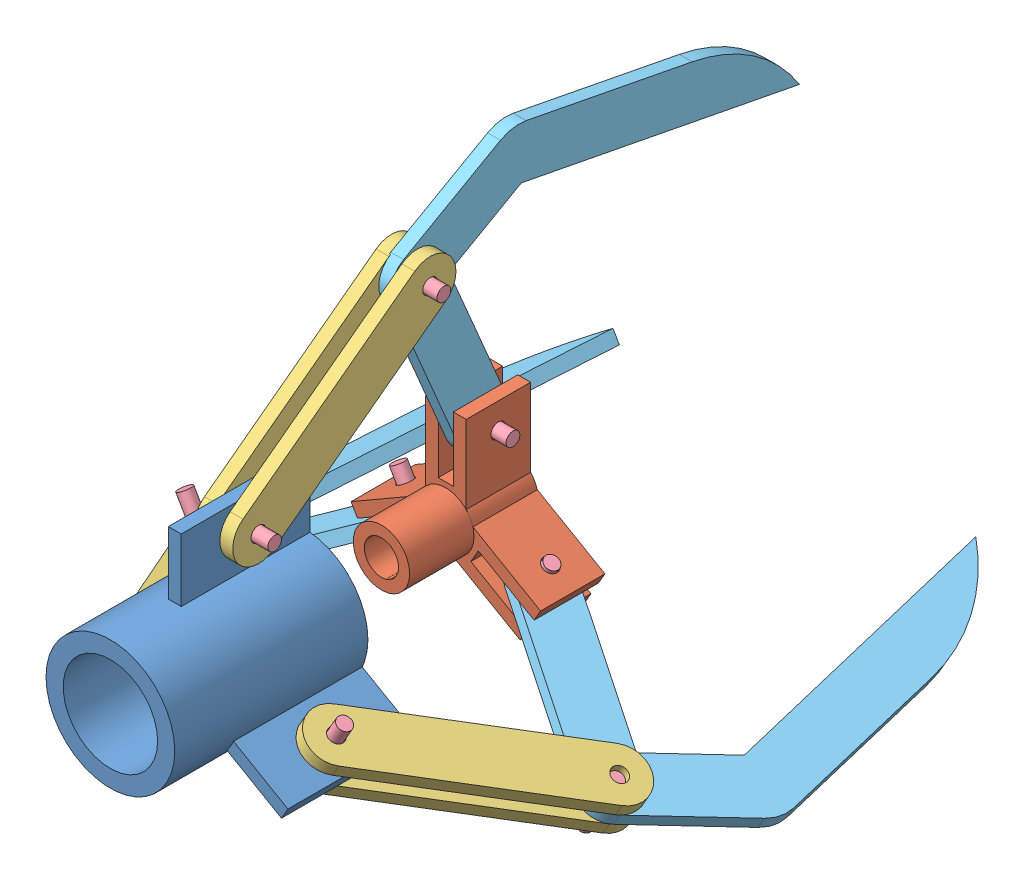
SolidWorks assembly 夾爪成品, configuration 預設. Lengths in mm.
Overall size (162.59 141.13 161.62).
20 component instances, 5 part files, 38 mates.
Components (placement in the parent):
- 電磁鐵放置區-1: 電磁鐵放置區 [預設] at (-9.8898 1.8598 -8.132) size (52.72 45.66 45)
- 三向夾物臂連接器-1: 三向夾物臂連接器 [預設] at (-9.8898 1.8598 -56.2732) x (-0.5 0.866025 0) z (0.866025 0.5 0) size (44.14 30 38.23)
- 夾物臂連接圓軸-1: 夾物臂連接圓軸 [預設] at (11.2751 -8.6277 6.868) x (0.519411 -0.299882 -0.800177) z (0.692973 -0.400088 0.599765) size (62 3 12)
- M3螺絲模擬-2: M3螺絲模擬 [預設] at (7.158 -15.7587 6.868) x (0.823092 -0.475212 0.310955) z (-0.269295 0.155477 0.950425) size (3.2 15 3.2)
- 夾物臂連接圓軸-2: 夾物臂連接圓軸 [預設] at (8.2751 -13.8239 6.868) x (0.519411 -0.299882 -0.800177) z (0.692973 -0.400088 0.599765) size (62 3 12)
- 夾物臂-1: 夾物臂 [預設] at (5.3596 -5.2124 -48.7732) x (0.797152 -0.460236 0.390809) z (0.338451 -0.195405 -0.920472) size (54.96 3 86)
- M3螺絲模擬-3: M3螺絲模擬 [預設] at (30.5045 -35.2978 -33.1408) x (0.866025 -0.5 0) z (0 0 1) size (3.2 15 3.2)
- M3螺絲模擬-4: M3螺絲模擬 [預設] at (-0.1826 -14.8118 -48.7732) x (-0.023911 0.013805 -0.999619) z (0.865695 -0.499809 -0.027609) size (3.2 15 3.2)
- 夾物臂-2: 夾物臂 [預設] at (-23.5141 -8.027 -48.7732) x (-0.797152 -0.460236 0.390809) z (-0.338451 -0.195405 -0.920472) size (54.96 3 86)
- M3螺絲模擬-5: M3螺絲模擬 [預設] at (-55.0827 -26.9864 -33.1408) x (0.866025 0.5 0) z (0 0 1) size (3.2 15 3.2)
- M3螺絲模擬-6: M3螺絲模擬 [預設] at (-20.9793 -12.4174 -48.7732) x (0.832749 0.480788 -0.274541) z (0.237759 0.13727 0.961576) size (3.2 15 3.2)
- 夾物臂連接圓軸-3: 夾物臂連接圓軸 [預設] at (-53.9002 -29.0345 -33.1408) x (0.519411 0.299882 0.800177) z (-0.692973 -0.400088 0.599765) size (62 3 12)
- 夾物臂連接圓軸-4: 夾物臂連接圓軸 [預設] at (-56.9002 -23.8383 -33.1408) x (0.519411 0.299882 0.800177) z (-0.692973 -0.400088 0.599765) size (62 3 12)
- M3螺絲模擬-7: M3螺絲模擬 [預設] at (-26.9948 -15.6596 6.868) x (0.855858 0.49413 0.152782) z (-0.132313 -0.076391 0.98826) size (3.2 15 3.2)
- M3螺絲模擬-8: M3螺絲模擬 [預設] at (-1.7523 18.6022 -48.7732) x (0 0.714644 0.699488) z (0 -0.699488 0.714644) size (3.2 15 3.2)
- M3螺絲模擬-9: M3螺絲模擬 [預設] at (-16.6217 25.4328 6.868) x (0 -0.623006 0.782217) z (0 0.782217 0.623006) size (3.2 15 3.2)
- M3螺絲模擬-10: M3螺絲模擬 [預設] at (-2.2035 55.421 -33.1408) x (0 0.967344 0.253466) z (0 -0.253466 0.967344) size (3.2 15 3.2)
- 夾物臂-3: 夾物臂 [預設] at (-11.6398 18.6022 -48.7732) x (0 0.920472 0.390809) z (0 0.390809 -0.920472) size (54.96 3 86)
- 夾物臂連接圓軸-5: 夾物臂連接圓軸 [預設] at (-11.3898 25.4328 6.868) x (0 0.599765 -0.800177) z (0 0.800177 0.599765) size (62 3 12)
- 夾物臂連接圓軸-6: 夾物臂連接圓軸 [預設] at (-5.3898 25.4328 6.868) x (0 0.599765 -0.800177) z (0 0.800177 0.599765) size (62 3 12)
Mates (geometry in assembly coordinates):
- 同軸心1: concentric anti-aligned: cylinder of 電磁鐵放置區-1 through (-9.8898 1.8598 -8.132) axis (0 0 1) radius 7.5; cylinder of 三向夾物臂連接器-1 through (-9.8898 1.8598 -26.2732) axis (0 0 -1) radius 6.575
- 平行(R)1: parallel aligned: plane of 電磁鐵放置區-1 through (14.9712 -14.2258 21.868) normal (-0.5 -0.866025 0); plane of 三向夾物臂連接器-1 through (-8.3248 -4.5286 -41.2732) normal (-0.5 -0.866025 0)
- 同軸心2: concentric aligned: cylinder of 電磁鐵放置區-1 through (24.7751 14.755 6.868) axis (-0.5 -0.866025 0) radius 1.75; cylinder of M3螺絲模擬-2 through (14.658 -2.7683 6.868) axis (-0.5 -0.866025 0) radius 1.6
- 同軸心3: concentric aligned: cylinder of 夾物臂連接圓軸-1 through (12.7751 -6.0296 6.868) axis (-0.5 -0.866025 0) radius 1.75; cylinder of M3螺絲模擬-2 through (14.658 -2.7683 6.868) axis (-0.5 -0.866025 0) radius 1.6
- 重合/共線/共點4: coincident anti-aligned: plane of 電磁鐵放置區-1 through (16.4712 -11.6277 21.868) normal (0.5 0.866025 0); plane of 夾物臂連接圓軸-1 through (11.2751 -8.6277 6.868) normal (-0.5 -0.866025 0)
- 重合/共線/共點5: coincident anti-aligned: plane of 電磁鐵放置區-1 through (14.9712 -14.2258 21.868) normal (-0.5 -0.866025 0); plane of 夾物臂連接圓軸-2 through (9.7751 -11.2258 6.868) normal (0.5 0.866025 0)
- 同軸心20: concentric aligned: cylinder of M3螺絲模擬-2 through (14.658 -2.7683 6.868) axis (-0.5 -0.866025 0) radius 1.6; cylinder of 夾物臂連接圓軸-2 through (9.7751 -11.2258 6.868) axis (-0.5 -0.866025 0) radius 1.75
- 同軸心21: concentric aligned: cylinder of 夾物臂連接圓軸-1 through (38.7456 -21.0238 -33.1408) axis (-0.5 -0.866025 0) radius 1.75; cylinder of 夾物臂連接圓軸-2 through (35.7456 -26.2199 -33.1408) axis (-0.5 -0.866025 0) radius 1.75
- 同軸心22: concentric aligned: cylinder of 夾物臂連接圓軸-2 through (35.7456 -26.2199 -33.1408) axis (-0.5 -0.866025 0) radius 1.75; cylinder of M3螺絲模擬-3 through (38.0045 -22.3074 -33.1408) axis (-0.5 -0.866025 0) radius 1.6
- 同軸心23: concentric anti-aligned: cylinder of 夾物臂-1 through (35.7456 -26.2199 -33.1408) axis (0.5 0.866025 0) radius 1.75; cylinder of M3螺絲模擬-3 through (38.0045 -22.3074 -33.1408) axis (-0.5 -0.866025 0) radius 1.6
- 重合/共線/共點6: coincident anti-aligned: plane of 夾物臂連接圓軸-2 through (9.7751 -11.2258 6.868) normal (0.5 0.866025 0); plane of 夾物臂-1 through (3.8596 -7.8105 -48.7732) normal (-0.5 -0.866025 0)
- 同軸心24: concentric aligned: cylinder of M3螺絲模擬-4 through (7.3174 -1.8214 -48.7732) axis (-0.5 -0.866025 0) radius 1.6; cylinder of 三向夾物臂連接器-1 through (9.7346 2.3653 -48.7732) axis (-0.5 -0.866025 0) radius 1.75
- 同軸心25: concentric aligned: cylinder of M3螺絲模擬-4 through (7.3174 -1.8214 -48.7732) axis (-0.5 -0.866025 0) radius 1.6; cylinder of 三向夾物臂連接器-1 through (9.7346 2.3653 -48.7732) axis (-0.5 -0.866025 0) radius 1.75
- 同軸心26: concentric anti-aligned: cylinder of 夾物臂-1 through (3.8596 -7.8105 -48.7732) axis (0.5 0.866025 0) radius 1.75; cylinder of M3螺絲模擬-4 through (7.3174 -1.8214 -48.7732) axis (-0.5 -0.866025 0) radius 1.6
- 同軸心27: concentric aligned: cylinder of M3螺絲模擬-6 through (-28.4793 0.573 -48.7732) axis (0.5 -0.866025 0) radius 1.6; cylinder of 夾物臂-2 through (-25.0141 -5.4289 -48.7732) axis (0.5 -0.866025 0) radius 1.75
- 同軸心28: concentric anti-aligned: cylinder of M3螺絲模擬-6 through (-28.4793 0.573 -48.7732) axis (0.5 -0.866025 0) radius 1.6; cylinder of 三向夾物臂連接器-1 through (-19.2641 -15.3882 -48.7732) axis (-0.5 0.866025 0) radius 1.75
- 同軸心29: concentric anti-aligned: cylinder of M3螺絲模擬-6 through (-28.4793 0.573 -48.7732) axis (0.5 -0.866025 0) radius 1.6; cylinder of 三向夾物臂連接器-1 through (-19.2641 -15.3882 -48.7732) axis (-0.5 0.866025 0) radius 1.75
- 重合/共線/共點7: coincident anti-aligned: plane of 三向夾物臂連接器-1 through (-28.7103 -11.027 -41.2732) normal (-0.5 0.866025 0); plane of 夾物臂-2 through (-23.5141 -8.027 -48.7732) normal (0.5 -0.866025 0)
- 同軸心30: concentric aligned: cylinder of M3螺絲模擬-5 through (-62.5827 -13.996 -33.1408) axis (0.5 -0.866025 0) radius 1.6; cylinder of 夾物臂連接圓軸-4 through (-58.4002 -21.2403 -33.1408) axis (0.5 -0.866025 0) radius 1.75
- 同軸心31: concentric aligned: cylinder of M3螺絲模擬-5 through (-62.5827 -13.996 -33.1408) axis (0.5 -0.866025 0) radius 1.6; cylinder of 夾物臂連接圓軸-3 through (-55.4002 -26.4364 -33.1408) axis (0.5 -0.866025 0) radius 1.75
- 同軸心32: concentric aligned: cylinder of M3螺絲模擬-5 through (-62.5827 -13.996 -33.1408) axis (0.5 -0.866025 0) radius 1.6; cylinder of 夾物臂-2 through (-56.9002 -23.8383 -33.1408) axis (0.5 -0.866025 0) radius 1.75
- 重合/共線/共點8: coincident anti-aligned: plane of 夾物臂-2 through (-23.5141 -8.027 -48.7732) normal (0.5 -0.866025 0); plane of 夾物臂連接圓軸-3 through (-55.4002 -26.4364 -33.1408) normal (-0.5 0.866025 0)
- 重合/共線/共點9: coincident anti-aligned: plane of 夾物臂-2 through (-25.0141 -5.4289 -48.7732) normal (-0.5 0.866025 0); plane of 夾物臂連接圓軸-4 through (-56.9002 -23.8383 -33.1408) normal (0.5 -0.866025 0)
- 同軸心33: concentric anti-aligned: cylinder of M3螺絲模擬-7 through (-34.4948 -2.6693 6.868) axis (0.5 -0.866025 0) radius 1.6; cylinder of 電磁鐵放置區-1 through (-16.0546 -34.6085 6.868) axis (-0.5 0.866025 0) radius 1.75
- 同軸心34: concentric aligned: cylinder of M3螺絲模擬-7 through (-34.4948 -2.6693 6.868) axis (0.5 -0.866025 0) radius 1.6; cylinder of 夾物臂連接圓軸-4 through (-32.4296 -6.2462 6.868) axis (0.5 -0.866025 0) radius 1.75
- 同軸心35: concentric aligned: cylinder of M3螺絲模擬-7 through (-34.4948 -2.6693 6.868) axis (0.5 -0.866025 0) radius 1.6; cylinder of 夾物臂連接圓軸-3 through (-29.4296 -11.4423 6.868) axis (0.5 -0.866025 0) radius 1.75
- 同軸心36: concentric anti-aligned: cylinder of M3螺絲模擬-9 through (-1.6217 25.4328 6.868) axis (-1 0 0) radius 1.6; cylinder of 電磁鐵放置區-1 through (-38.3898 25.4328 6.868) axis (1 0 0) radius 1.75
- 同軸心37: concentric anti-aligned: cylinder of M3螺絲模擬-9 through (-1.6217 25.4328 6.868) axis (-1 0 0) radius 1.6; cylinder of 夾物臂連接圓軸-5 through (-14.3898 25.4328 6.868) axis (1 0 0) radius 1.75
- 同軸心38: concentric anti-aligned: cylinder of M3螺絲模擬-9 through (-1.6217 25.4328 6.868) axis (-1 0 0) radius 1.6; cylinder of 夾物臂連接圓軸-6 through (-8.3898 25.4328 6.868) axis (1 0 0) radius 1.75
- 重合/共線/共點10: coincident anti-aligned: plane of 電磁鐵放置區-1 through (-11.3898 31.4328 21.868) normal (-1 0 0); plane of 夾物臂連接圓軸-5 through (-11.3898 25.4328 6.868) normal (1 0 0)
- 重合/共線/共點11: coincident anti-aligned: plane of 電磁鐵放置區-1 through (-8.3898 31.4328 21.868) normal (1 0 0); plane of 夾物臂連接圓軸-6 through (-8.3898 25.4328 6.868) normal (-1 0 0)
- 同軸心39: concentric anti-aligned: cylinder of 夾物臂-3 through (-8.6398 18.6022 -48.7732) axis (-1 0 0) radius 1.75; cylinder of M3螺絲模擬-8 through (-16.7523 18.6022 -48.7732) axis (1 0 0) radius 1.6
- 同軸心40: concentric anti-aligned: cylinder of 夾物臂-3 through (-8.6398 18.6022 -48.7732) axis (-1 0 0) radius 1.75; cylinder of 三向夾物臂連接器-1 through (-20.1398 18.6022 -48.7732) axis (1 0 0) radius 1.75
- 同軸心41: concentric anti-aligned: cylinder of 夾物臂-3 through (-8.6398 18.6022 -48.7732) axis (-1 0 0) radius 1.75; cylinder of 三向夾物臂連接器-1 through (-20.1398 18.6022 -48.7732) axis (1 0 0) radius 1.75
- 重合/共線/共點13: coincident anti-aligned: plane of 三向夾物臂連接器-1 through (-11.6398 24.6022 -41.2732) normal (1 0 0); plane of 夾物臂-3 through (-11.6398 18.6022 -48.7732) normal (-1 0 0)
- 同軸心43: concentric anti-aligned: cylinder of M3螺絲模擬-10 through (-17.2035 55.421 -33.1408) axis (1 0 0) radius 1.6; cylinder of 夾物臂-3 through (-8.6398 55.421 -33.1408) axis (-1 0 0) radius 1.75
- 同軸心44: concentric aligned: cylinder of M3螺絲模擬-10 through (-17.2035 55.421 -33.1408) axis (1 0 0) radius 1.6; cylinder of 夾物臂連接圓軸-6 through (-8.3898 55.421 -33.1408) axis (1 0 0) radius 1.75
- 同軸心45: concentric aligned: cylinder of M3螺絲模擬-10 through (-17.2035 55.421 -33.1408) axis (1 0 0) radius 1.6; cylinder of 夾物臂連接圓軸-5 through (-14.3898 55.421 -33.1408) axis (1 0 0) radius 1.75
